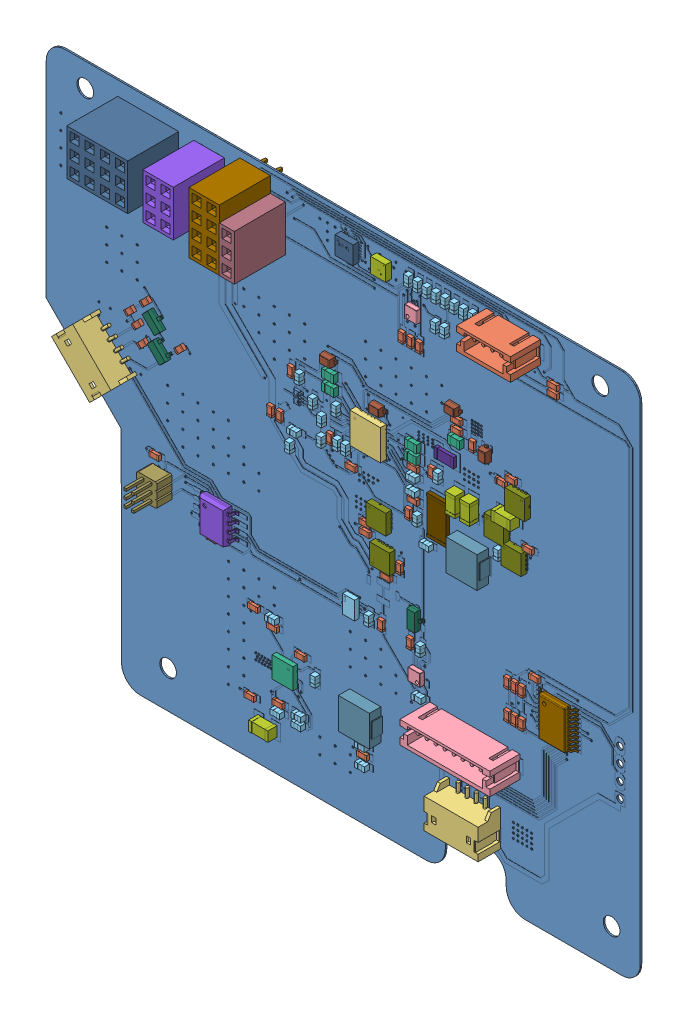
SolidWorks assembly pcb_charger, configuration Default. Lengths in mm.
Overall size (99.42 87.69 11.66).
416 component instances, 31 part files, 0 mates.
Components (placement in the parent):
- Dip_charger_charger-1: Dip_charger_charger [Default] at origin size (99.42 87.69 0.33)
- Resistor 0603_charger-1: Resistor 0603_charger [Default] at (28.88 -11.721 0.352) x (0 1 0) z (1 0 0) size (1.6 0.51 0.86)
- Resistor 0603_charger-2: Resistor 0603_charger [Default] at (27.686 -11.672 0.352) x (0 1 0) z (1 0 0) size (1.6 0.51 0.86)
- Resistor 0603_charger-3: Resistor 0603_charger [Default] at (26.492 -11.67 0.352) x (0 1 0) z (1 0 0) size (1.6 0.51 0.86)
- Resistor 0603_charger-4: Resistor 0603_charger [Default] at (-16.408 -35.14 0.352) x (1 0 0) z (0 -1 0) size (1.6 0.51 0.86)
- Resistor 0603_charger-5: Resistor 0603_charger [Default] at (31.051 -8.788 0.352) x (-1 0 0) z (0 1 0) size (1.6 0.51 0.86)
- Resistor 0603_charger-6: Resistor 0603_charger [Default] at (26.492 -16.475 0.352) x (0 1 0) z (1 0 0) size (1.6 0.51 0.86)
- Resistor 0603_charger-7: Resistor 0603_charger [Default] at (27.672 -16.486 0.352) x (0 1 0) z (1 0 0) size (1.6 0.51 0.86)
- Resistor 0603_charger-8: Resistor 0603_charger [Default] at (13.868 12.383 0.352) x (0 -1 0) z (-1 0 0) size (1.6 0.51 0.86)
- Resistor 0603_charger-9: Resistor 0603_charger [Default] at (10.807 11.481 0.352) x (1 0 0) z (0 -1 0) size (1.6 0.51 0.86)
- Resistor 0603_charger-10: Resistor 0603_charger [Default] at (10.236 -14.111 0.352) x (0 -1 0) z (-1 0 0) size (1.6 0.51 0.86)
- Resistor 0603_charger-11: Resistor 0603_charger [Default] at (-11.455 7.837 0.352) x (0 -1 0) z (-1 0 0) size (1.6 0.51 0.86)
- Resistor 0603_charger-12: Resistor 0603_charger [Default] at (-13.005 7.837 0.352) x (0 -1 0) z (-1 0 0) size (1.6 0.51 0.86)
- Resistor 0603_charger-13: Resistor 0603_charger [Default] at (5.436 -13.906 0.352) x (0 -1 0) z (-1 0 0) size (1.6 0.51 0.86)
- Resistor 0603_charger-14: Resistor 0603_charger [Default] at (-22.772 -15.443 0.352) x (1 0 0) z (0 -1 0) size (1.6 0.51 0.86)
- Resistor 0603_charger-15: Resistor 0603_charger [Default] at (28.88 -16.498 0.352) x (0 1 0) z (1 0 0) size (1.6 0.51 0.86)
- Resistor 0603_charger-16: Resistor 0603_charger [Default] at (0.471 6.401 0.352) x (-1 0 0) z (0 1 0) size (1.6 0.51 0.86)
- Resistor 0603_charger-17: Resistor 0603_charger [Default] at (-3.099 8.775 0.352) x (0 1 0) z (1 0 0) size (1.6 0.51 0.86)
- Resistor 0603_charger-18: Resistor 0603_charger [Default] at (-32.283 -8.294 0.352) x (1 0 0) z (0 -1 0) size (1.6 0.51 0.86)
- Resistor 0603_charger-19: Resistor 0603_charger [Default] at (-12.612 -23.266 0.352) x (-1 0 0) z (0 1 0) size (1.6 0.51 0.86)
- Resistor 0603_charger-20: Resistor 0603_charger [Default] at (-7.964 -25.121 0.352) x (1 0 0) z (0 -1 0) size (1.6 0.51 0.86)
- Resistor 0603_charger-21: Resistor 0603_charger [Default] at (-15.785 -21.971 0.352) x (-1 0 0) z (0 1 0) size (1.6 0.51 0.86)
- Resistor 0603_charger-22: Resistor 0603_charger [Default] at (-11.696 -33.858 0.352) x (-1 0 0) z (0 1 0) size (1.6 0.51 0.86)
- Resistor 0603_charger-23: Resistor 0603_charger [Default] at (2.401 -34.265 0.352) x (-1 0 0) z (0 1 0) size (1.6 0.51 0.86)
- Resistor 0603_charger-24: Resistor 0603_charger [Default] at (11.747 29.425 0.352) x (0 1 0) z (1 0 0) size (1.6 0.51 0.86)
- Resistor 0603_charger-25: Resistor 0603_charger [Default] at (10.319 29.425 0.352) x (0 1 0) z (1 0 0) size (1.6 0.51 0.86)
- Resistor 0603_charger-26: Resistor 0603_charger [Default] at (8.89 29.425 0.352) x (0 1 0) z (1 0 0) size (1.6 0.51 0.86)
- Resistor 0603_charger-27: Resistor 0603_charger [Default] at (34.143 33.777 0.352) x (-1 0 0) z (0 1 0) size (1.6 0.51 0.86)
- Resistor 0603_charger-28: Resistor 0603_charger [Default] at (34.155 35.017 0.352) x (-1 0 0) z (0 1 0) size (1.6 0.51 0.86)
- Resistor 0603_charger-29: Resistor 0603_charger [Default] at (27.139 17.882 0.352) x (1 0 0) z (0 -1 0) size (1.6 0.51 0.86)
- Resistor 0603_charger-30: Resistor 0603_charger [Default] at (18.046 21.92 0.352) x (1 0 0) z (0 -1 0) size (1.6 0.51 0.86)
- Resistor 0603_charger-31: Resistor 0603_charger [Default] at (10.809 6.782 0.352) x (-1 0 0) z (0 1 0) size (1.6 0.51 0.86)
- Resistor 0603_charger-32: Resistor 0603_charger [Default] at (10.008 4.484 0.352) x (0 1 0) z (1 0 0) size (1.6 0.51 0.86)
- Resistor 0603_charger-33: Resistor 0603_charger [Default] at (25.439 16.713 0.352) x (-1 0 0) z (0 1 0) size (1.6 0.51 0.86)
- Resistor 0603_charger-34: Resistor 0603_charger [Default] at (20.65 19.57 0.352) x (0 1 0) z (1 0 0) size (1.6 0.51 0.86)
- Resistor 0603_charger-35: Resistor 0603_charger [Default] at (18.046 20.472 0.352) x (1 0 0) z (0 -1 0) size (1.6 0.51 0.86)
- Resistor 0603_charger-36: Resistor 0603_charger [Default] at (-9.601 15.203 0.352) x (0 -1 0) z (-1 0 0) size (1.6 0.51 0.86)
- Resistor 0603_charger-37: Resistor 0603_charger [Default] at (2.808 -1.88 0.352) x (-1 0 0) z (0 1 0) size (1.6 0.51 0.86)
- Resistor 0603_charger-38: Resistor 0603_charger [Default] at (2.808 -0.533 0.352) x (-1 0 0) z (0 1 0) size (1.6 0.51 0.86)
- Resistor 0603_charger-39: Resistor 0603_charger [Default] at (8.484 -4.154 0.352) x (0 1 0) z (1 0 0) size (1.6 0.51 0.86)
- Resistor 0603_charger-40: Resistor 0603_charger [Default] at (6.313 -6.502 0.352) x (-1 0 0) z (0 1 0) size (1.6 0.51 0.86)
- Resistor 0603_charger-41: Resistor 0603_charger [Default] at (29.921 9.232 0.352) x (1 0 0) z (0 -1 0) size (1.6 0.51 0.86)
- S4B-ZR-SM4A-TF_charger-1: S4B-ZR-SM4A-TF_charger [Default] at (20.532 -30.6503 0.322) x (1 0 0) z (0 -1 0) size (9 3.7 6.5)
- B8B-PH-SM4_charger-1: B8B-PH-SM4_charger [Default] at (20.777 -21.285 0.322) x (-1 0 0) z (0 1 0) size (15 5 5.2)
- Capacitor 0603_charger-1: Capacitor 0603_charger [Default] at (-1.9513 13.6149 0.352) x (0 -1 0) z (-1 0 0) size (1.6 0.86 0.86)
- Capacitor 0603_charger-2: Capacitor 0603_charger [Default] at (-5.8365 12.7133 0.352) x (0 -1 0) z (-1 0 0) size (1.6 0.86 0.86)
- Capacitor 0603_charger-3: Capacitor 0603_charger [Default] at (-4.3622 10.9092 0.352) x (0 -1 0) z (-1 0 0) size (1.6 0.86 0.86)
- Capacitor 0603_charger-4: Capacitor 0603_charger [Default] at (-4.4248 7.8826 0.352) x (0 -1 0) z (-1 0 0) size (1.6 0.86 0.86)
- Capacitor 0603_charger-5: Capacitor 0603_charger [Default] at (15.0381 12.376 0.352) x (0 1 0) z (1 0 0) size (1.6 0.86 0.86)
- Capacitor 0603_charger-6: Capacitor 0603_charger [Default] at (12.1131 -14.0605 0.352) x (0 -1 0) z (-1 0 0) size (1.6 0.86 0.86)
- Capacitor 0603_charger-7: Capacitor 0603_charger [Default] at (-0.3478 8.7752 0.352) x (0 1 0) z (1 0 0) size (1.6 0.86 0.86)
- Capacitor 0603_charger-8: Capacitor 0603_charger [Default] at (11.8302 -21.1446 0.352) x (1 0 0) z (0 -1 0) size (1.6 0.86 0.86)
- Capacitor 0603_charger-9: Capacitor 0603_charger [Default] at (-9.6722 4.4422 0.352) x (0 1 0) z (1 0 0) size (1.6 0.86 0.86)
- Capacitor 0603_charger-10: Capacitor 0603_charger [Default] at (-8.9409 6.8961 0.352) x (1 0 0) z (0 -1 0) size (1.6 0.86 0.86)
- Capacitor 0603_charger-11: Capacitor 0603_charger [Default] at (-8.0696 15.1512 0.352) x (0 1 0) z (1 0 0) size (1.6 0.86 0.86)
- Capacitor 0603_charger-12: Capacitor 0603_charger [Default] at (-1.7225 8.7881 0.352) x (0 -1 0) z (-1 0 0) size (1.6 0.86 0.86)
- Capacitor 0603_charger-13: Capacitor 0603_charger [Default] at (13.204 38.2945 0.352) x (0 1 0) z (1 0 0) size (1.6 0.86 0.86)
- Capacitor 0603_charger-14: Capacitor 0603_charger [Default] at (3.504 -13.9653 0.352) x (0 -1 0) z (-1 0 0) size (1.6 0.86 0.86)
- Capacitor 0603_charger-15: Capacitor 0603_charger [Default] at (-11.716 -35.1131 0.352) x (1 0 0) z (0 -1 0) size (1.6 0.86 0.86)
- Capacitor 0603_charger-16: Capacitor 0603_charger [Default] at (25.0943 6.3252 0.352) x (0 -1 0) z (-1 0 0) size (1.6 0.86 0.86)
- Capacitor 0603_charger-17: Capacitor 0603_charger [Default] at (10.8545 10.2268 0.352) x (-1 0 0) z (0 1 0) size (1.6 0.86 0.86)
- Capacitor 0603_charger-18: Capacitor 0603_charger [Default] at (11.5842 4.4989 0.352) x (0 -1 0) z (-1 0 0) size (1.6 0.86 0.86)
- Capacitor 0603_charger-19: Capacitor 0603_charger [Default] at (13.1222 1.4787 0.352) x (-1 0 0) z (0 1 0) size (1.6 0.86 0.86)
- Capacitor 0603_charger-20: Capacitor 0603_charger [Default] at (10.8077 8.1218 0.352) x (1 0 0) z (0 -1 0) size (1.6 0.86 0.86)
- Capacitor 0603_charger-21: Capacitor 0603_charger [Default] at (-8.2414 -35.1325 0.352) x (-1 0 0) z (0 1 0) size (1.6 0.86 0.86)
- Capacitor 0603_charger-22: Capacitor 0603_charger [Default] at (-12.6042 -21.9995 0.352) x (1 0 0) z (0 -1 0) size (1.6 0.86 0.86)
- Capacitor 0603_charger-23: Capacitor 0603_charger [Default] at (-8.1907 -33.8485 0.352) x (-1 0 0) z (0 1 0) size (1.6 0.86 0.86)
- Capacitor 0603_charger-24: Capacitor 0603_charger [Default] at (-5.4446 -27.2439 0.352) x (0 -1 0) z (-1 0 0) size (1.6 0.86 0.86)
- Capacitor 0603_charger-25: Capacitor 0603_charger [Default] at (2.3902 -32.8002 0.352) x (-1 0 0) z (0 1 0) size (1.6 0.86 0.86)
- Capacitor 0603_charger-26: Capacitor 0603_charger [Default] at (2.4043 -35.7051 0.352) x (-1 0 0) z (0 1 0) size (1.6 0.86 0.86)
- Capacitor 0603_charger-27: Capacitor 0603_charger [Default] at (19.3161 38.2834 0.352) x (0 1 0) z (1 0 0) size (1.6 0.86 0.86)
- Capacitor 0603_charger-28: Capacitor 0603_charger [Default] at (11.6642 38.3734 0.352) x (0 1 0) z (1 0 0) size (1.6 0.86 0.86)
- Capacitor 0603_charger-29: Capacitor 0603_charger [Default] at (10.156 38.3892 0.352) x (0 1 0) z (1 0 0) size (1.6 0.86 0.86)
- Capacitor 0603_charger-30: Capacitor 0603_charger [Default] at (14.7438 38.2787 0.352) x (0 1 0) z (1 0 0) size (1.6 0.86 0.86)
- Capacitor 0603_charger-31: Capacitor 0603_charger [Default] at (20.8296 38.3465 0.352) x (0 1 0) z (1 0 0) size (1.6 0.86 0.86)
- Capacitor 0603_charger-32: Capacitor 0603_charger [Default] at (16.2678 38.2945 0.352) x (0 1 0) z (1 0 0) size (1.6 0.86 0.86)
- Capacitor 0603_charger-33: Capacitor 0603_charger [Default] at (17.776 38.3103 0.352) x (0 1 0) z (1 0 0) size (1.6 0.86 0.86)
- Capacitor 0805_charger-1: Capacitor 0805_charger [Default] at (-3.0255 17.9719 0.352) x (-1 0 0) z (0 1 0) size (2 0.76 1.31)
- Capacitor 0805_charger-2: Capacitor 0805_charger [Default] at (10.8092 14.789 0.352) x (-1 0 0) z (0 1 0) size (2 0.76 1.31)
- Capacitor 0805_charger-3: Capacitor 0805_charger [Default] at (17.9668 18.9444 0.352) x (1 0 0) z (0 -1 0) size (2 0.76 1.31)
- Capacitor 0805_charger-4: Capacitor 0805_charger [Default] at (-2.9864 16.0419 0.352) x (-1 0 0) z (0 1 0) size (2 0.76 1.31)
- Capacitor 0805_charger-5: Capacitor 0805_charger [Default] at (10.7597 13.0346 0.352) x (1 0 0) z (0 -1 0) size (2 0.76 1.31)
- Capacitor 1206_charger-1: Capacitor 1206_charger [Default] at (18.2068 10.432 0.352) x (0 1 0) z (1 0 0) size (3.2 1.56 1.66)
- Capacitor 1206_charger-2: Capacitor 1206_charger [Default] at (20.601 10.5132 0.352) x (0 1 0) z (1 0 0) size (3.2 1.56 1.66)
- Capacitor 1206_charger-3: Capacitor 1206_charger [Default] at (26.6312 12.3622 0.352) x (-1 0 0) z (0 1 0) size (3.2 1.56 1.66)
- Capacitor 1206_charger-4: Capacitor 1206_charger [Default] at (-13.7778 -38.251 0.352) x (1 0 0) z (0 -1 0) size (3.2 1.56 1.66)
- 2x3 female header 2_54mm pitch_charger-1: 2x3 female header 2_54mm pitch_charger [По умолчанию] at (-22.2612 33.8213 0.322) x (1 0 0) z (0 -1 0) size (5.08 11.66 7.62)
- 2x4 female header 2_54mm pitch_charger-1: 2x4 female header 2_54mm pitch_charger [По умолчанию] at (-14.5851 32.5594 0.322) x (1 0 0) z (0 -1 0) size (5.08 11.66 10.16)
- 3x4 female header 2_54mm pitch_charger-2: 3x4 female header 2_54mm pitch_charger [По умолчанию] at (-29.8695 38.8987 0.322) x (0 1 0) z (1 0 0) size (7.62 11.66 10.16)
- SOD323F-1_charger-1: SOD323F-1_charger [Default] at (17.443 23.368 0.322) x (-1 0 0) z (0 0 1) size (2.5 1.35 1)
- SOD323F-1_charger-2: SOD323F-1_charger [Default] at (-3.361 20.041 0.322) x (-1 0 0) z (0 0 1) size (2.5 1.35 1)
- SOD323F-1_charger-3: SOD323F-1_charger [Default] at (4.859 17.043 0.322) size (2.5 1.35 1)
- SFH1412B_SFH1412B_charger-1: SFH1412B_SFH1412B_charger [Default] at (5.512 -9.325 0.322) x (-1 0 0) z (0 0 1) size (5.4 3.49 0)
- Hole_Hole_charger-1: Hole_Hole_charger [Default] at (41.681 38.583 0.322)
- Hole_Hole_charger-2: Hole_Hole_charger [Default] at (-44.221 38.583 0.322)
- Hole_Hole_charger-3: Hole_Hole_charger [Default] at (-30.404 -38.252 0.322)
- Hole_Hole_charger-4: Hole_Hole_charger [Default] at (43.561 -38.557 0.322)
- Hole_Hole_charger-5: Hole_Hole_charger [Default] at (-73.304 -10.897 0.322)
- Hole_Hole_charger-6: Hole_Hole_charger [Default] at (-73.304 94.031 0.322)
- ISP_Header_charger-1: ISP_Header_charger [Default] at (-31.42 -13.0419 0.322) x (0 1 0) z (1 0 0) size (3.81 7.85 3.4)
- 1x3 female header 2_54mm pitch_charger-1: 1x3 female header 2_54mm pitch_charger [По умолчанию] at (-12.093 32.5232 0.322) x (1 0 0) z (0 -1 0) size (2.54 11.66 7.62)
- IHLP-2020BZ-01_charger-1: IHLP-2020BZ-01_charger [По умолчанию] at (20.568 3.327 0.322) x (-1 0 0) z (0 1 0) size (5.49 2 5.18)
- IHLP-2020BZ-01_charger-2: IHLP-2020BZ-01_charger [По умолчанию] at (2.616 -28.55 0.322) x (1 0 0) z (0 -1 0) size (5.49 2 5.18)
- Capacitor 0603_charger-34: Capacitor 0603_charger [Default] at (14.631 33.9408 0.352) x (0 -1 0) z (-1 0 0) size (1.6 0.86 0.86)
- Capacitor 0603_charger-35: Capacitor 0603_charger [Default] at (16.1353 33.9777 0.352) x (0 1 0) z (1 0 0) size (1.6 0.86 0.86)
- SOT 23_charger-1: SOT 23_charger [Default] at (11.186 -10.051 0.872) x (0 1 0) z (1 0 0) size (3 1.1 2.5)
- TDFN-8-EP_3x3mm_charger-1: TDFN-8-EP_3x3mm_charger [По умолчанию] at (24.943 9.881 0.322) x (-1 0 0) z (0 1 0) size (3.36 1 3.36)
- TDFN-8-EP_3x3mm_charger-2: TDFN-8-EP_3x3mm_charger [По умолчанию] at (27.838 7.061 0.322) x (-1 0 0) z (0 1 0) size (3.36 1 3.36)
- TDFN-8-EP_3x3mm_charger-3: TDFN-8-EP_3x3mm_charger [По умолчанию] at (28.423 15.291 0.322) x (0 1 0) z (1 0 0) size (3.36 1 3.36)
- TDFN-8-EP_3x3mm_charger-4: TDFN-8-EP_3x3mm_charger [По умолчанию] at (5.283 1.626 0.322) x (-1 0 0) z (0 1 0) size (3.36 1 3.36)
- TDFN-8-EP_3x3mm_charger-5: TDFN-8-EP_3x3mm_charger [По умолчанию] at (5.893 -3.81 0.322) x (0 -1 0) z (-1 0 0) size (3.36 1 3.36)
- SOD323F-1_charger-4: SOD323F-1_charger [Default] at (22.8584 19.4212 0.322) x (0 -1 0) z (0 0 1) size (2.5 1.35 1)
- SOT 23_charger-2: SOT 23_charger [Default] at (-31.2873 7.3715 0.872) x (0.707107 -0.707107 0) z (-0.707107 -0.707107 0) size (3 1.1 2.5)
- SOT 23_charger-3: SOT 23_charger [Default] at (-32.1347 11.2245 0.872) x (-0.707107 0.707107 0) z (0.707107 0.707107 0) size (3 1.1 2.5)
- Resistor 1206_charger-1: Resistor 1206_charger [Default] at (16.151 15.697 0.352) x (-1 0 0) z (0 1 0) size (3.2 0.56 1.66)
- Resistor 0603_charger-42: Resistor 0603_charger [Default] at (-35.196 9.153 0.352) x (-0.707107 -0.707107 0) z (-0.707107 0.707107 0) size (1.6 0.51 0.86)
- Resistor 0603_charger-43: Resistor 0603_charger [Default] at (-33.841 13.123 0.352) x (0.707107 0.707107 0) z (0.707107 -0.707107 0) size (1.6 0.51 0.86)
- Resistor 0603_charger-44: Resistor 0603_charger [Default] at (-28.084 9.178 0.352) x (-0.707107 -0.707107 0) z (-0.707107 0.707107 0) size (1.6 0.51 0.86)
- Resistor 0603_charger-45: Resistor 0603_charger [Default] at (-34.3196 6.8199 0.352) x (0.707107 0.707107 0) z (0.707107 -0.707107 0) size (1.6 0.51 0.86)
- Resistor 0603_charger-46: Resistor 0603_charger [Default] at (-36.44 10.499 0.352) x (-0.707107 -0.707107 0) z (-0.707107 0.707107 0) size (1.6 0.51 0.86)
- Resistor 2512_charger-1: Resistor 2512_charger [Default] at (14.986 6.115 0.352) x (0 1 0) z (1 0 0) size (6.35 0.61 3.26)
- 4xRes_0402_charger-1: 4xRes_0402_charger [По умолчанию] at (-8.6314 11.9181 0.322) x (0 1 0) z (1 0 0) size (2 0.37 1)
- B4B-PH-SM4(LF)(SN)_charger-1: B4B-PH-SM4(LF)(SN)_charger [Default] at (27.229 40.301 0.322) x (-1 0 0) z (0 1 0) size (9 5 5.2)
- Static_Via_Static_Via_charger-1: Static_Via_Static_Via_charger [Default] at (1.016 2.286 0.322)
- Static_Via_Static_Via_charger-2: Static_Via_Static_Via_charger [Default] at (1.778 2.286 0.322)
- Static_Via_Static_Via_charger-3: Static_Via_Static_Via_charger [Default] at (1.778 1.524 0.322)
- Static_Via_Static_Via_charger-4: Static_Via_Static_Via_charger [Default] at (1.016 1.524 0.322)
- Static_Via_Static_Via_charger-5: Static_Via_Static_Via_charger [Default] at (1.016 0.762 0.322)
- Static_Via_Static_Via_charger-6: Static_Via_Static_Via_charger [Default] at (1.778 0.762 0.322)
- Static_Via_Static_Via_charger-7: Static_Via_Static_Via_charger [Default] at (2.54 2.286 0.322)
- Static_Via_Static_Via_charger-8: Static_Via_Static_Via_charger [Default] at (2.54 1.524 0.322)
- Static_Via_Static_Via_charger-9: Static_Via_Static_Via_charger [Default] at (13.97 7.366 0.322)
- Static_Via_Static_Via_charger-10: Static_Via_Static_Via_charger [Default] at (14.986 7.366 0.322)
- Static_Via_Static_Via_charger-11: Static_Via_Static_Via_charger [Default] at (16.002 7.366 0.322)
- Static_Via_Static_Via_charger-12: Static_Via_Static_Via_charger [Default] at (16.002 6.35 0.322)
- Static_Via_Static_Via_charger-13: Static_Via_Static_Via_charger [Default] at (16.002 5.334 0.322)
- Static_Via_Static_Via_charger-14: Static_Via_Static_Via_charger [Default] at (14.986 6.35 0.322)
- Static_Via_Static_Via_charger-15: Static_Via_Static_Via_charger [Default] at (13.97 6.35 0.322)
- Static_Via_Static_Via_charger-16: Static_Via_Static_Via_charger [Default] at (13.97 5.334 0.322)
- Static_Via_Static_Via_charger-17: Static_Via_Static_Via_charger [Default] at (14.986 5.334 0.322)
- Static_Via_Static_Via_charger-18: Static_Via_Static_Via_charger [Default] at (2.286 13.97 0.322)
- Static_Via_Static_Via_charger-19: Static_Via_Static_Via_charger [Default] at (3.302 13.97 0.322)
- Static_Via_Static_Via_charger-20: Static_Via_Static_Via_charger [Default] at (2.794 12.954 0.322)
- Static_Via_Static_Via_charger-21: Static_Via_Static_Via_charger [Default] at (3.81 12.954 0.322)
- Static_Via_Static_Via_charger-22: Static_Via_Static_Via_charger [Default] at (4.318 13.97 0.322)
- Static_Via_Static_Via_charger-23: Static_Via_Static_Via_charger [Default] at (4.826 12.954 0.322)
- Static_Via_Static_Via_charger-24: Static_Via_Static_Via_charger [Default] at (2.54 13.462 0.322)
- Static_Via_Static_Via_charger-25: Static_Via_Static_Via_charger [Default] at (3.556 13.462 0.322)
- Static_Via_Static_Via_charger-26: Static_Via_Static_Via_charger [Default] at (2.286 12.446 0.322)
- Static_Via_Static_Via_charger-27: Static_Via_Static_Via_charger [Default] at (2.54 11.938 0.322)
- Static_Via_Static_Via_charger-28: Static_Via_Static_Via_charger [Default] at (4.572 13.462 0.322)
- Static_Via_Static_Via_charger-29: Static_Via_Static_Via_charger [Default] at (2.794 11.43 0.322)
- Static_Via_Static_Via_charger-30: Static_Via_Static_Via_charger [Default] at (3.302 12.446 0.322)
- Static_Via_Static_Via_charger-31: Static_Via_Static_Via_charger [Default] at (3.556 11.938 0.322)
- Static_Via_Static_Via_charger-32: Static_Via_Static_Via_charger [Default] at (3.81 11.43 0.322)
- Static_Via_Static_Via_charger-33: Static_Via_Static_Via_charger [Default] at (4.318 12.446 0.322)
- Static_Via_Static_Via_charger-34: Static_Via_Static_Via_charger [Default] at (4.572 11.938 0.322)
- Static_Via_Static_Via_charger-35: Static_Via_Static_Via_charger [Default] at (4.826 11.43 0.322)
- Static_Via_Static_Via_charger-36: Static_Via_Static_Via_charger [Default] at (4.572 6.35 0.322)
- Static_Via_Static_Via_charger-37: Static_Via_Static_Via_charger [Default] at (2.286 6.35 0.322)
- Static_Via_Static_Via_charger-38: Static_Via_Static_Via_charger [Default] at (3.048 6.35 0.322)
- Static_Via_Static_Via_charger-39: Static_Via_Static_Via_charger [Default] at (3.81 6.35 0.322)
- Static_Via_Static_Via_charger-40: Static_Via_Static_Via_charger [Default] at (2.286 5.588 0.322)
- Static_Via_Static_Via_charger-41: Static_Via_Static_Via_charger [Default] at (3.048 5.588 0.322)
- Static_Via_Static_Via_charger-42: Static_Via_Static_Via_charger [Default] at (2.286 4.826 0.322)
- Static_Via_Static_Via_charger-43: Static_Via_Static_Via_charger [Default] at (1.524 5.588 0.322)
- Static_Via_Static_Via_charger-44: Static_Via_Static_Via_charger [Default] at (1.524 4.826 0.322)
- Static_Via_Static_Via_charger-45: Static_Via_Static_Via_charger [Default] at (3.81 5.588 0.322)
- Static_Via_Static_Via_charger-46: Static_Via_Static_Via_charger [Default] at (-15.748 -28.702 0.322)
- Static_Via_Static_Via_charger-47: Static_Via_Static_Via_charger [Default] at (-15.24 -28.702 0.322)
- Static_Via_Static_Via_charger-48: Static_Via_Static_Via_charger [Default] at (-14.732 -28.702 0.322)
- Static_Via_Static_Via_charger-49: Static_Via_Static_Via_charger [Default] at (-14.224 -28.702 0.322)
- Static_Via_Static_Via_charger-50: Static_Via_Static_Via_charger [Default] at (-13.716 -28.702 0.322)
- Static_Via_Static_Via_charger-51: Static_Via_Static_Via_charger [Default] at (-13.208 -28.702 0.322)
- Static_Via_Static_Via_charger-52: Static_Via_Static_Via_charger [Default] at (-15.494 -29.21 0.322)
- Static_Via_Static_Via_charger-53: Static_Via_Static_Via_charger [Default] at (-14.986 -29.21 0.322)
- Static_Via_Static_Via_charger-54: Static_Via_Static_Via_charger [Default] at (-14.478 -29.21 0.322)
- Static_Via_Static_Via_charger-55: Static_Via_Static_Via_charger [Default] at (-13.97 -29.21 0.322)
- Static_Via_Static_Via_charger-56: Static_Via_Static_Via_charger [Default] at (-13.462 -29.21 0.322)
- Static_Via_Static_Via_charger-57: Static_Via_Static_Via_charger [Default] at (-15.24 -29.718 0.322)
- Static_Via_Static_Via_charger-58: Static_Via_Static_Via_charger [Default] at (-14.732 -29.718 0.322)
- Static_Via_Static_Via_charger-59: Static_Via_Static_Via_charger [Default] at (-14.224 -29.718 0.322)
- Static_Via_Static_Via_charger-60: Static_Via_Static_Via_charger [Default] at (-13.716 -29.718 0.322)
- Static_Via_Static_Via_charger-61: Static_Via_Static_Via_charger [Default] at (-13.208 -29.718 0.322)
- Static_Via_Static_Via_charger-62: Static_Via_Static_Via_charger [Default] at (-15.748 -29.718 0.322)
- Static_Via_Static_Via_charger-63: Static_Via_Static_Via_charger [Default] at (-3.912 14.681 0.322)
- Static_Via_Static_Via_charger-64: Static_Via_Static_Via_charger [Default] at (-2.87 5.41 0.322)
- Static_Via_Static_Via_charger-65: Static_Via_Static_Via_charger [Default] at (-3.404 5.944 0.322)
- Static_Via_Static_Via_charger-66: Static_Via_Static_Via_charger [Default] at (-30.48 2.54 0.322)
- Static_Via_Static_Via_charger-67: Static_Via_Static_Via_charger [Default] at (20.32 22.86 0.322)
- Static_Via_Static_Via_charger-68: Static_Via_Static_Via_charger [Default] at (20.32 22.352 0.322)
- Static_Via_Static_Via_charger-69: Static_Via_Static_Via_charger [Default] at (20.32 21.844 0.322)
- Static_Via_Static_Via_charger-70: Static_Via_Static_Via_charger [Default] at (20.32 21.336 0.322)
- Static_Via_Static_Via_charger-71: Static_Via_Static_Via_charger [Default] at (20.828 22.86 0.322)
- Static_Via_Static_Via_charger-72: Static_Via_Static_Via_charger [Default] at (20.828 22.352 0.322)
- Static_Via_Static_Via_charger-73: Static_Via_Static_Via_charger [Default] at (20.828 21.844 0.322)
- Static_Via_Static_Via_charger-74: Static_Via_Static_Via_charger [Default] at (20.828 21.336 0.322)
- Static_Via_Static_Via_charger-75: Static_Via_Static_Via_charger [Default] at (21.336 22.86 0.322)
- Static_Via_Static_Via_charger-76: Static_Via_Static_Via_charger [Default] at (21.336 22.352 0.322)
- Static_Via_Static_Via_charger-77: Static_Via_Static_Via_charger [Default] at (21.336 21.844 0.322)
- Static_Via_Static_Via_charger-78: Static_Via_Static_Via_charger [Default] at (21.336 21.336 0.322)
- Static_Via_Static_Via_charger-79: Static_Via_Static_Via_charger [Default] at (21.844 22.86 0.322)
- Static_Via_Static_Via_charger-80: Static_Via_Static_Via_charger [Default] at (21.844 22.352 0.322)
- Static_Via_Static_Via_charger-81: Static_Via_Static_Via_charger [Default] at (21.844 21.844 0.322)
- Static_Via_Static_Via_charger-82: Static_Via_Static_Via_charger [Default] at (21.844 21.336 0.322)
- Static_Via_Static_Via_charger-83: Static_Via_Static_Via_charger [Default] at (18.034 -32.766 0.322)
- Static_Via_Static_Via_charger-84: Static_Via_Static_Via_charger [Default] at (18.796 -32.766 0.322)
- Static_Via_Static_Via_charger-85: Static_Via_Static_Via_charger [Default] at (19.558 -32.766 0.322)
- Static_Via_Static_Via_charger-86: Static_Via_Static_Via_charger [Default] at (20.32 -32.766 0.322)
- Static_Via_Static_Via_charger-87: Static_Via_Static_Via_charger [Default] at (20.32 -33.274 0.322)
- Static_Via_Static_Via_charger-88: Static_Via_Static_Via_charger [Default] at (19.558 -33.274 0.322)
- Static_Via_Static_Via_charger-89: Static_Via_Static_Via_charger [Default] at (18.796 -33.274 0.322)
- Static_Via_Static_Via_charger-90: Static_Via_Static_Via_charger [Default] at (18.034 -33.274 0.322)
- Static_Via_Static_Via_charger-91: Static_Via_Static_Via_charger [Default] at (18.034 -33.782 0.322)
- Static_Via_Static_Via_charger-92: Static_Via_Static_Via_charger [Default] at (18.796 -33.782 0.322)
- Static_Via_Static_Via_charger-93: Static_Via_Static_Via_charger [Default] at (19.558 -33.782 0.322)
- Static_Via_Static_Via_charger-94: Static_Via_Static_Via_charger [Default] at (20.32 -33.782 0.322)
- Static_Via_Static_Via_charger-95: Static_Via_Static_Via_charger [Default] at (20.32 -34.29 0.322)
- Static_Via_Static_Via_charger-96: Static_Via_Static_Via_charger [Default] at (19.558 -34.29 0.322)
- Static_Via_Static_Via_charger-97: Static_Via_Static_Via_charger [Default] at (18.796 -34.29 0.322)
- Static_Via_Static_Via_charger-98: Static_Via_Static_Via_charger [Default] at (18.034 -34.29 0.322)
- Static_Via_Static_Via_charger-99: Static_Via_Static_Via_charger [Default] at (27.178 -31.75 0.322)
- Static_Via_Static_Via_charger-100: Static_Via_Static_Via_charger [Default] at (27.94 -31.75 0.322)
- Static_Via_Static_Via_charger-101: Static_Via_Static_Via_charger [Default] at (28.702 -31.75 0.322)
- Static_Via_Static_Via_charger-102: Static_Via_Static_Via_charger [Default] at (29.464 -31.75 0.322)
- Static_Via_Static_Via_charger-103: Static_Via_Static_Via_charger [Default] at (30.226 -31.75 0.322)
- Static_Via_Static_Via_charger-104: Static_Via_Static_Via_charger [Default] at (29.464 -32.512 0.322)
- Static_Via_Static_Via_charger-105: Static_Via_Static_Via_charger [Default] at (30.226 -32.512 0.322)
- Static_Via_Static_Via_charger-106: Static_Via_Static_Via_charger [Default] at (28.702 -32.512 0.322)
- Static_Via_Static_Via_charger-107: Static_Via_Static_Via_charger [Default] at (27.94 -32.512 0.322)
- Static_Via_Static_Via_charger-108: Static_Via_Static_Via_charger [Default] at (27.178 -32.512 0.322)
- Static_Via_Static_Via_charger-109: Static_Via_Static_Via_charger [Default] at (27.178 -33.274 0.322)
- Static_Via_Static_Via_charger-110: Static_Via_Static_Via_charger [Default] at (27.94 -33.274 0.322)
- Static_Via_Static_Via_charger-111: Static_Via_Static_Via_charger [Default] at (28.702 -33.274 0.322)
- Static_Via_Static_Via_charger-112: Static_Via_Static_Via_charger [Default] at (29.464 -33.274 0.322)
- Static_Via_Static_Via_charger-113: Static_Via_Static_Via_charger [Default] at (30.226 -33.274 0.322)
- Static_Via_Static_Via_charger-114: Static_Via_Static_Via_charger [Default] at (30.226 -34.036 0.322)
- Static_Via_Static_Via_charger-115: Static_Via_Static_Via_charger [Default] at (29.464 -34.036 0.322)
- Static_Via_Static_Via_charger-116: Static_Via_Static_Via_charger [Default] at (28.702 -34.036 0.322)
- Static_Via_Static_Via_charger-117: Static_Via_Static_Via_charger [Default] at (27.94 -34.036 0.322)
- Static_Via_Static_Via_charger-118: Static_Via_Static_Via_charger [Default] at (27.178 -34.036 0.322)
- Static_Via_Static_Via_charger-119: Static_Via_Static_Via_charger [Default] at (11.43 16.764 0.322)
- Static_Via_Static_Via_charger-120: Static_Via_Static_Via_charger [Default] at (12.192 16.764 0.322)
- Static_Via_Static_Via_charger-121: Static_Via_Static_Via_charger [Default] at (12.954 16.764 0.322)
- Static_Via_Static_Via_charger-122: Static_Via_Static_Via_charger [Default] at (13.716 16.764 0.322)
- Static_Via_Static_Via_charger-123: Static_Via_Static_Via_charger [Default] at (11.43 16.256 0.322)
- Static_Via_Static_Via_charger-124: Static_Via_Static_Via_charger [Default] at (12.192 16.256 0.322)
- Static_Via_Static_Via_charger-125: Static_Via_Static_Via_charger [Default] at (12.954 16.256 0.322)
- Static_Via_Static_Via_charger-126: Static_Via_Static_Via_charger [Default] at (13.716 16.256 0.322)
- Static_Via_Static_Via_charger-127: Static_Via_Static_Via_charger [Default] at (13.716 15.748 0.322)
- Static_Via_Static_Via_charger-128: Static_Via_Static_Via_charger [Default] at (12.954 15.748 0.322)
- Static_Via_Static_Via_charger-129: Static_Via_Static_Via_charger [Default] at (12.192 15.748 0.322)
- Static_Via_Static_Via_charger-130: Static_Via_Static_Via_charger [Default] at (11.43 15.748 0.322)
- Static_Via_Static_Via_charger-131: Static_Via_Static_Via_charger [Default] at (-21.336 -10.414 0.322)
- Static_Via_Static_Via_charger-132: Static_Via_Static_Via_charger [Default] at (-20.32 -10.414 0.322)
- Static_Via_Static_Via_charger-133: Static_Via_Static_Via_charger [Default] at (-20.828 -10.922 0.322)
- Static_Via_Static_Via_charger-134: Static_Via_Static_Via_charger [Default] at (-21.844 -10.922 0.322)
- Static_Via_Static_Via_charger-135: Static_Via_Static_Via_charger [Default] at (-20.32 -17.78 0.322)
- Static_Via_Static_Via_charger-136: Static_Via_Static_Via_charger [Default] at (-17.78 -17.78 0.322)
- Static_Via_Static_Via_charger-137: Static_Via_Static_Via_charger [Default] at (-15.24 -17.78 0.322)
- Static_Via_Static_Via_charger-138: Static_Via_Static_Via_charger [Default] at (-12.7 -17.78 0.322)
- Static_Via_Static_Via_charger-139: Static_Via_Static_Via_charger [Default] at (-12.7 -20.32 0.322)
- Static_Via_Static_Via_charger-140: Static_Via_Static_Via_charger [Default] at (-15.24 -20.32 0.322)
- Static_Via_Static_Via_charger-141: Static_Via_Static_Via_charger [Default] at (-17.78 -20.32 0.322)
- Static_Via_Static_Via_charger-142: Static_Via_Static_Via_charger [Default] at (-20.32 -20.32 0.322)
- Static_Via_Static_Via_charger-143: Static_Via_Static_Via_charger [Default] at (-20.32 -22.86 0.322)
- Static_Via_Static_Via_charger-144: Static_Via_Static_Via_charger [Default] at (-17.78 -22.86 0.322)
- Static_Via_Static_Via_charger-145: Static_Via_Static_Via_charger [Default] at (-17.78 -25.4 0.322)
- Static_Via_Static_Via_charger-146: Static_Via_Static_Via_charger [Default] at (-20.32 -25.4 0.322)
- Static_Via_Static_Via_charger-147: Static_Via_Static_Via_charger [Default] at (-17.78 -27.94 0.322)
- Static_Via_Static_Via_charger-148: Static_Via_Static_Via_charger [Default] at (-20.32 -27.94 0.322)
- Static_Via_Static_Via_charger-149: Static_Via_Static_Via_charger [Default] at (-17.78 -30.48 0.322)
- Static_Via_Static_Via_charger-150: Static_Via_Static_Via_charger [Default] at (-20.32 -30.48 0.322)
- Static_Via_Static_Via_charger-151: Static_Via_Static_Via_charger [Default] at (-17.78 -33.02 0.322)
- Static_Via_Static_Via_charger-152: Static_Via_Static_Via_charger [Default] at (-20.32 -33.02 0.322)
- Static_Via_Static_Via_charger-153: Static_Via_Static_Via_charger [Default] at (-20.32 -35.56 0.322)
- Static_Via_Static_Via_charger-154: Static_Via_Static_Via_charger [Default] at (0 -17.78 0.322)
- Static_Via_Static_Via_charger-155: Static_Via_Static_Via_charger [Default] at (2.54 -17.78 0.322)
- Static_Via_Static_Via_charger-156: Static_Via_Static_Via_charger [Default] at (5.08 -17.78 0.322)
- Static_Via_Static_Via_charger-157: Static_Via_Static_Via_charger [Default] at (5.08 -20.32 0.322)
- Static_Via_Static_Via_charger-158: Static_Via_Static_Via_charger [Default] at (2.54 -20.32 0.322)
- Static_Via_Static_Via_charger-159: Static_Via_Static_Via_charger [Default] at (0 -20.32 0.322)
- Static_Via_Static_Via_charger-160: Static_Via_Static_Via_charger [Default] at (0 -22.86 0.322)
- Static_Via_Static_Via_charger-161: Static_Via_Static_Via_charger [Default] at (2.54 -22.86 0.322)
- Static_Via_Static_Via_charger-162: Static_Via_Static_Via_charger [Default] at (5.08 -22.86 0.322)
- Static_Via_Static_Via_charger-163: Static_Via_Static_Via_charger [Default] at (7.62 -22.86 0.322)
- Static_Via_Static_Via_charger-164: Static_Via_Static_Via_charger [Default] at (7.62 -20.32 0.322)
- Static_Via_Static_Via_charger-165: Static_Via_Static_Via_charger [Default] at (10.16 -22.86 0.322)
- Static_Via_Static_Via_charger-166: Static_Via_Static_Via_charger [Default] at (0 -38.1 0.322)
- Static_Via_Static_Via_charger-167: Static_Via_Static_Via_charger [Default] at (-2.54 -38.1 0.322)
- Static_Via_Static_Via_charger-168: Static_Via_Static_Via_charger [Default] at (-5.08 -38.1 0.322)
- Static_Via_Static_Via_charger-169: Static_Via_Static_Via_charger [Default] at (-5.08 -35.56 0.322)
- Static_Via_Static_Via_charger-170: Static_Via_Static_Via_charger [Default] at (-2.54 -35.56 0.322)
- Static_Via_Static_Via_charger-171: Static_Via_Static_Via_charger [Default] at (0 -35.56 0.322)
- Static_Via_Static_Via_charger-172: Static_Via_Static_Via_charger [Default] at (2.54 20.32 0.322)
- Static_Via_Static_Via_charger-173: Static_Via_Static_Via_charger [Default] at (-15.24 17.78 0.322)
- Static_Via_Static_Via_charger-174: Static_Via_Static_Via_charger [Default] at (19.05 15.24 0.322)
- Static_Via_Static_Via_charger-175: Static_Via_Static_Via_charger [Default] at (19.05 14.478 0.322)
- Static_Via_Static_Via_charger-176: Static_Via_Static_Via_charger [Default] at (19.05 13.716 0.322)
- Static_Via_Static_Via_charger-177: Static_Via_Static_Via_charger [Default] at (19.812 13.716 0.322)
- Static_Via_Static_Via_charger-178: Static_Via_Static_Via_charger [Default] at (19.812 14.478 0.322)
- Static_Via_Static_Via_charger-179: Static_Via_Static_Via_charger [Default] at (19.812 15.24 0.322)
- Static_Via_Static_Via_charger-180: Static_Via_Static_Via_charger [Default] at (20.574 15.24 0.322)
- Static_Via_Static_Via_charger-181: Static_Via_Static_Via_charger [Default] at (20.574 14.478 0.322)
- Static_Via_Static_Via_charger-182: Static_Via_Static_Via_charger [Default] at (20.574 13.716 0.322)
- Static_Via_Static_Via_charger-183: Static_Via_Static_Via_charger [Default] at (21.336 13.716 0.322)
- Static_Via_Static_Via_charger-184: Static_Via_Static_Via_charger [Default] at (21.336 14.478 0.322)
- Static_Via_Static_Via_charger-185: Static_Via_Static_Via_charger [Default] at (21.336 15.24 0.322)
- Static_Via_Static_Via_charger-186: Static_Via_Static_Via_charger [Default] at (5.08 20.32 0.322)
- Static_Via_Static_Via_charger-187: Static_Via_Static_Via_charger [Default] at (7.62 20.32 0.322)
- Static_Via_Static_Via_charger-188: Static_Via_Static_Via_charger [Default] at (10.16 20.32 0.322)
- Static_Via_Static_Via_charger-189: Static_Via_Static_Via_charger [Default] at (12.7 20.32 0.322)
- Static_Via_Static_Via_charger-190: Static_Via_Static_Via_charger [Default] at (2.54 22.86 0.322)
- Static_Via_Static_Via_charger-191: Static_Via_Static_Via_charger [Default] at (5.08 22.86 0.322)
- Static_Via_Static_Via_charger-192: Static_Via_Static_Via_charger [Default] at (7.62 22.86 0.322)
- Static_Via_Static_Via_charger-193: Static_Via_Static_Via_charger [Default] at (10.16 22.86 0.322)
- Static_Via_Static_Via_charger-194: Static_Via_Static_Via_charger [Default] at (12.7 22.86 0.322)
- Static_Via_Static_Via_charger-195: Static_Via_Static_Via_charger [Default] at (2.54 25.4 0.322)
- Static_Via_Static_Via_charger-196: Static_Via_Static_Via_charger [Default] at (5.08 25.4 0.322)
- Static_Via_Static_Via_charger-197: Static_Via_Static_Via_charger [Default] at (7.62 25.4 0.322)
- Static_Via_Static_Via_charger-198: Static_Via_Static_Via_charger [Default] at (10.16 25.4 0.322)
- Static_Via_Static_Via_charger-199: Static_Via_Static_Via_charger [Default] at (12.7 25.4 0.322)
- Static_Via_Static_Via_charger-200: Static_Via_Static_Via_charger [Default] at (15.24 25.4 0.322)
- Static_Via_Static_Via_charger-201: Static_Via_Static_Via_charger [Default] at (15.24 22.86 0.322)
- Static_Via_Static_Via_charger-202: Static_Via_Static_Via_charger [Default] at (-15.24 20.32 0.322)
- Static_Via_Static_Via_charger-203: Static_Via_Static_Via_charger [Default] at (-17.78 20.32 0.322)
- Static_Via_Static_Via_charger-204: Static_Via_Static_Via_charger [Default] at (-12.7 17.78 0.322)
- Static_Via_Static_Via_charger-205: Static_Via_Static_Via_charger [Default] at (-12.7 20.32 0.322)
- Static_Via_Static_Via_charger-206: Static_Via_Static_Via_charger [Default] at (-12.7 15.24 0.322)
- Static_Via_Static_Via_charger-207: Static_Via_Static_Via_charger [Default] at (-10.16 17.78 0.322)
- Static_Via_Static_Via_charger-208: Static_Via_Static_Via_charger [Default] at (-10.16 20.32 0.322)
- Static_Via_Static_Via_charger-209: Static_Via_Static_Via_charger [Default] at (-7.62 17.78 0.322)
- Static_Via_Static_Via_charger-210: Static_Via_Static_Via_charger [Default] at (-7.62 20.32 0.322)
- Static_Via_Static_Via_charger-211: Static_Via_Static_Via_charger [Default] at (-17.78 22.86 0.322)
- Static_Via_Static_Via_charger-212: Static_Via_Static_Via_charger [Default] at (-15.24 22.86 0.322)
- Static_Via_Static_Via_charger-213: Static_Via_Static_Via_charger [Default] at (-12.7 22.86 0.322)
- Static_Via_Static_Via_charger-214: Static_Via_Static_Via_charger [Default] at (-10.16 22.86 0.322)
- Static_Via_Static_Via_charger-215: Static_Via_Static_Via_charger [Default] at (-7.62 22.86 0.322)
- Static_Via_Static_Via_charger-216: Static_Via_Static_Via_charger [Default] at (-43.18 25.4 0.322)
- Static_Via_Static_Via_charger-217: Static_Via_Static_Via_charger [Default] at (-45.72 25.4 0.322)
- Static_Via_Static_Via_charger-218: Static_Via_Static_Via_charger [Default] at (-48.26 25.4 0.322)
- Static_Via_Static_Via_charger-219: Static_Via_Static_Via_charger [Default] at (-48.26 27.94 0.322)
- Static_Via_Static_Via_charger-220: Static_Via_Static_Via_charger [Default] at (-45.72 27.94 0.322)
- Static_Via_Static_Via_charger-221: Static_Via_Static_Via_charger [Default] at (-43.18 27.94 0.322)
- Static_Via_Static_Via_charger-222: Static_Via_Static_Via_charger [Default] at (-43.18 30.48 0.322)
- Static_Via_Static_Via_charger-223: Static_Via_Static_Via_charger [Default] at (-45.72 30.48 0.322)
- Static_Via_Static_Via_charger-224: Static_Via_Static_Via_charger [Default] at (-48.26 30.48 0.322)
- Static_Via_Static_Via_charger-225: Static_Via_Static_Via_charger [Default] at (-48.26 33.02 0.322)
- Static_Via_Static_Via_charger-226: Static_Via_Static_Via_charger [Default] at (-45.72 33.02 0.322)
- Static_Via_Static_Via_charger-227: Static_Via_Static_Via_charger [Default] at (-43.18 33.02 0.322)
- Static_Via_Static_Via_charger-228: Static_Via_Static_Via_charger [Default] at (-27.94 2.54 0.322)
- Static_Via_Static_Via_charger-229: Static_Via_Static_Via_charger [Default] at (-25.4 2.54 0.322)
- Static_Via_Static_Via_charger-230: Static_Via_Static_Via_charger [Default] at (-22.86 2.54 0.322)
- Static_Via_Static_Via_charger-231: Static_Via_Static_Via_charger [Default] at (-20.32 2.54 0.322)
- Static_Via_Static_Via_charger-232: Static_Via_Static_Via_charger [Default] at (-30.48 0 0.322)
- Static_Via_Static_Via_charger-233: Static_Via_Static_Via_charger [Default] at (-27.94 0 0.322)
- Static_Via_Static_Via_charger-234: Static_Via_Static_Via_charger [Default] at (-25.4 0 0.322)
- Static_Via_Static_Via_charger-235: Static_Via_Static_Via_charger [Default] at (-22.86 0 0.322)
- Static_Via_Static_Via_charger-236: Static_Via_Static_Via_charger [Default] at (-20.32 0 0.322)
- Static_Via_Static_Via_charger-237: Static_Via_Static_Via_charger [Default] at (-17.78 0 0.322)
- Static_Via_Static_Via_charger-238: Static_Via_Static_Via_charger [Default] at (-17.78 -2.54 0.322)
- Static_Via_Static_Via_charger-239: Static_Via_Static_Via_charger [Default] at (-20.32 -2.54 0.322)
- Static_Via_Static_Via_charger-240: Static_Via_Static_Via_charger [Default] at (-22.86 -2.54 0.322)
- Static_Via_Static_Via_charger-241: Static_Via_Static_Via_charger [Default] at (-25.4 -2.54 0.322)
- Static_Via_Static_Via_charger-242: Static_Via_Static_Via_charger [Default] at (-27.94 -2.54 0.322)
- Static_Via_Static_Via_charger-243: Static_Via_Static_Via_charger [Default] at (-30.48 -2.54 0.322)
- Static_Via_Static_Via_charger-244: Static_Via_Static_Via_charger [Default] at (-27.94 -5.08 0.322)
- Static_Via_Static_Via_charger-245: Static_Via_Static_Via_charger [Default] at (-25.4 -5.08 0.322)
- Static_Via_Static_Via_charger-246: Static_Via_Static_Via_charger [Default] at (-22.86 -5.08 0.322)
- Static_Via_Static_Via_charger-247: Static_Via_Static_Via_charger [Default] at (-20.32 -5.08 0.322)
- Static_Via_Static_Via_charger-248: Static_Via_Static_Via_charger [Default] at (-17.78 -5.08 0.322)
- Static_Via_Static_Via_charger-249: Static_Via_Static_Via_charger [Default] at (-15.24 -5.08 0.322)
- Static_Via_Static_Via_charger-250: Static_Via_Static_Via_charger [Default] at (-15.24 -2.54 0.322)
- Static_Via_Static_Via_charger-251: Static_Via_Static_Via_charger [Default] at (-40.64 20.32 0.322)
- Static_Via_Static_Via_charger-252: Static_Via_Static_Via_charger [Default] at (-38.1 20.32 0.322)
- Static_Via_Static_Via_charger-253: Static_Via_Static_Via_charger [Default] at (-35.56 20.32 0.322)
- Static_Via_Static_Via_charger-254: Static_Via_Static_Via_charger [Default] at (-35.56 17.78 0.322)
- Static_Via_Static_Via_charger-255: Static_Via_Static_Via_charger [Default] at (-38.1 17.78 0.322)
- Static_Via_Static_Via_charger-256: Static_Via_Static_Via_charger [Default] at (-40.64 17.78 0.322)
- Static_Via_Static_Via_charger-257: Static_Via_Static_Via_charger [Default] at (-40.64 15.24 0.322)
- Static_Via_Static_Via_charger-258: Static_Via_Static_Via_charger [Default] at (-38.1 15.24 0.322)
- Static_Via_Static_Via_charger-259: Static_Via_Static_Via_charger [Default] at (-35.56 15.24 0.322)
- Static_Via_Static_Via_charger-260: Static_Via_Static_Via_charger [Default] at (-0.317 38.1 0.322)
- Static_Via_Static_Via_charger-261: Static_Via_Static_Via_charger [Default] at (0.317 38.1 0.322)
- Static_Via_Static_Via_charger-262: Static_Via_Static_Via_charger [Default] at (0.317 37.465 0.322)
- Static_Via_Static_Via_charger-263: Static_Via_Static_Via_charger [Default] at (-0.317 37.465 0.322)
- Static_Via_Static_Via_charger-264: Static_Via_Static_Via_charger [Default] at (10.439 33.909 0.322)
- Static_Via_Static_Via_charger-265: Static_Via_Static_Via_charger [Default] at (11.201 33.909 0.322)
- Static_Via_Static_Via_charger-266: Static_Via_Static_Via_charger [Default] at (-2.54 39.37 0.322)
- Static_Via_Static_Via_charger-267: Static_Via_Static_Via_charger [Default] at (-3.81 39.37 0.322)
- Static_Via_Static_Via_charger-268: Static_Via_Static_Via_charger [Default] at (10.795 31.75 0.322)
- Static_Via_Static_Via_charger-269: Static_Via_Static_Via_charger [Default] at (9.525 31.75 0.322)
- Static_Via_Static_Via_charger-270: Static_Via_Static_Via_charger [Default] at (-5.08 39.37 0.322)
- Static_Via_Static_Via_charger-271: Static_Via_Static_Via_charger [Default] at (-3.81 38.1 0.322)
- Static_Via_Static_Via_charger-272: Static_Via_Static_Via_charger [Default] at (-3.81 36.83 0.322)
- Static_Via_Static_Via_charger-273: Static_Via_Static_Via_charger [Default] at (3.175 36.195 0.322)
- Static_Via_Static_Via_charger-274: Static_Via_Static_Via_charger [Default] at (2.54 36.83 0.322)
- Static_Via_Static_Via_charger-275: Static_Via_Static_Via_charger [Default] at (5.08 36.195 0.322)
- Static_Via_Static_Via_charger-276: Static_Via_Static_Via_charger [Default] at (6.35 36.195 0.322)
- Static_Via_Static_Via_charger-277: Static_Via_Static_Via_charger [Default] at (7.62 36.83 0.322)
- Static_Via_Static_Via_charger-278: Static_Via_Static_Via_charger [Default] at (7.62 39.37 0.322)
- Static_Via_Static_Via_charger-279: Static_Via_Static_Via_charger [Default] at (-34.925 1.905 0.322)
- Static_Via_Static_Via_charger-280: Static_Via_Static_Via_charger [Default] at (-41.91 6.985 0.322)
- Static_Via_Static_Via_charger-281: Static_Via_Static_Via_charger [Default] at (-41.91 8.89 0.322)
- Static_Via_Static_Via_charger-282: Static_Via_Static_Via_charger [Default] at (-40.005 8.89 0.322)
- Static_Via_Static_Via_charger-283: Static_Via_Static_Via_charger [Default] at (40.208 -13.411 0.322)
- S4B-ZR-SM4A-TF_charger-2: S4B-ZR-SM4A-TF_charger [Default] at (-38.6894 4.7194 0.322) x (0.707107 -0.707107 0) z (-0.707107 -0.707107 0) size (9 3.7 6.5)
- VQFN-32_charger-1: VQFN-32_charger [Default] at (3.505 12.675 0.322) size (5.12 5.12 1.01)
- SON8-2x2mm_charger-1: SON8-2x2mm_charger [Default] at (11.4176 -18.2572 0.7356) x (-1 0 0) z (0 -1 0) size (2 0.8 2)
- DFN8_3_0x2_0mm_0_50_charger-1: DFN8_3_0x2_0mm_0_50_charger [Standard] at (0.523 -13.576 0.322) x (0 -1 0) z (-1 0 0) size (3 0.81 2)
- TPS54320_charger-1: TPS54320_charger [Default] at (-10.547 -28.617 0.322) x (-1 0 0) z (0 1 0) size (3.5 0.8 3.5)
- HCLGA-10L_LPS25H_charger-1: HCLGA-10L_LPS25H_charger [Default] at (5.639 37.895 0.322) x (-1 0 0) z (0 1 0) size (2.5 1.03 2.5)
- SO_IC8_charger-1: SO_IC8_charger [Default] at (-21.666 -11.938 1.222) x (0 1 0) z (1 0 0) size (5.5 1.6 6.3)
- TSSOP-20_charger-1: TSSOP-20_charger [Default] at (34.777 -13.085 0.322) x (0 -1 0) z (0 0 1) size (6.6 6.55 1.2)
- SON8-2x2mm_charger-2: SON8-2x2mm_charger [Default] at (10.8512 33.868 0.7434) x (0 1 0) z (-1 0 0) size (2 0.8 2)
- QFN24-3x3_MPU9250_charger-1: QFN24-3x3_MPU9250_charger [Default] at (-0.016 37.818 0.322) x (-1 0 0) z (0 1 0) size (3.02 1.05 3.02)
